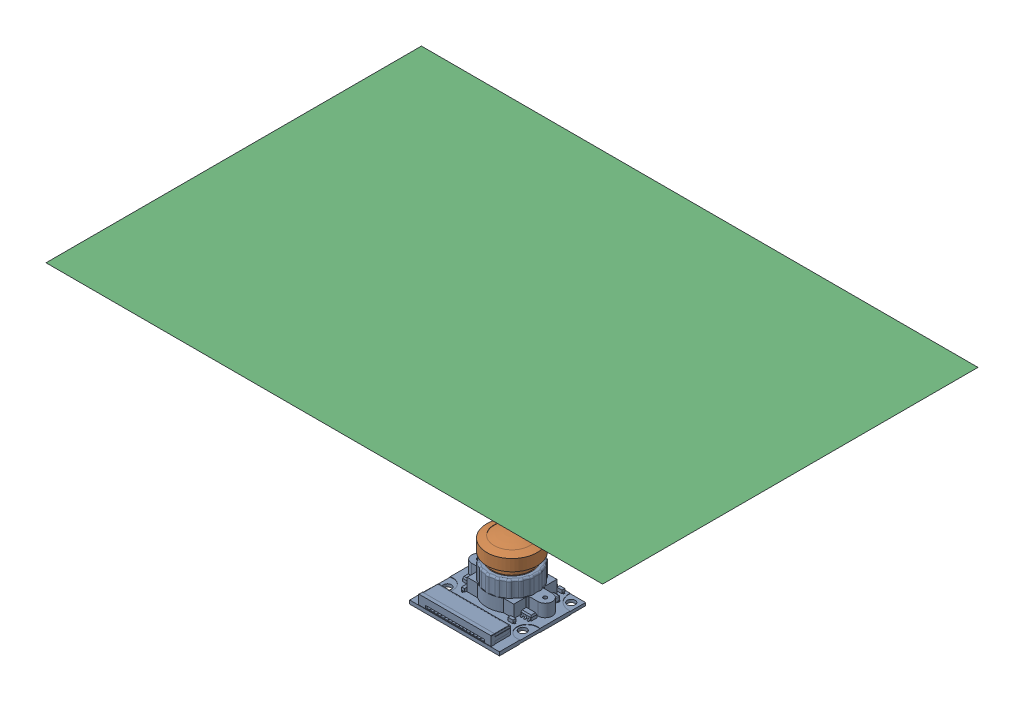
SolidWorks assembly rpiCameraMAssembly, configuration Default. Lengths in mm.
Overall size (155.08 69.5 104.6).
3 component instances, 3 part files, 8 mates.
Components (placement in the parent):
- rpiCameraM-1: rpiCameraM [Default] at origin size (25 10.53 24)
- rpiCameraM_lens-1: rpiCameraM_lens [Default] at (0 2 -4) x (-0.986591 0 -0.163209) z (0.163209 0 -0.986591) size (14 13.7 14)
- kameraBlickwinkel-1: kameraBlickwinkel [Standard] at (0 -0.1116 -4) x (-1 0 0) z (0 0 1) size (155.08 52.3 104.6)
Mates (geometry in assembly coordinates):
- Coincident1: coordinate: point of rpiCameraM-1
- Concentric1: concentric aligned: circle of rpiCameraM-1; circle of rpiCameraM_lens-1
- Deckungsgleich2: coincident: sphere of rpiCameraM_lens-1; point of kameraBlickwinkel-1
- Abstand1: distance = 2 mm anti-aligned: plane of rpiCameraM_lens-1 through (0 11 -4) normal (0 -1 0); plane of rpiCameraM-1 through (0 9 -4) normal (0 1 0)
- Parallel2: parallel anti-aligned: plane of rpiCameraM-1 through (0 0 0) normal (0 -1 0); plane of kameraBlickwinkel-1 through (0 68 -4) normal (0 1 0)
- Parallel3: parallel: plane of rpiCameraM-1 through (12.5 1 12) normal (0 0 1); line of kameraBlickwinkel-1 through (-77.5379 68 48.3) axis (1 0 0)
- Symmetrisch1: symmetric anti-aligned: line of kameraBlickwinkel-1 through (-77.5379 68 -56.3) axis (0 0 1); line of kameraBlickwinkel-1 through (77.5379 68 48.3) axis (0 0 -1)
- Symmetrisch2: symmetric anti-aligned: line of kameraBlickwinkel-1 through (-77.5379 68 48.3) axis (1 0 0); line of kameraBlickwinkel-1 through (77.5379 68 -56.3) axis (-1 0 0)
